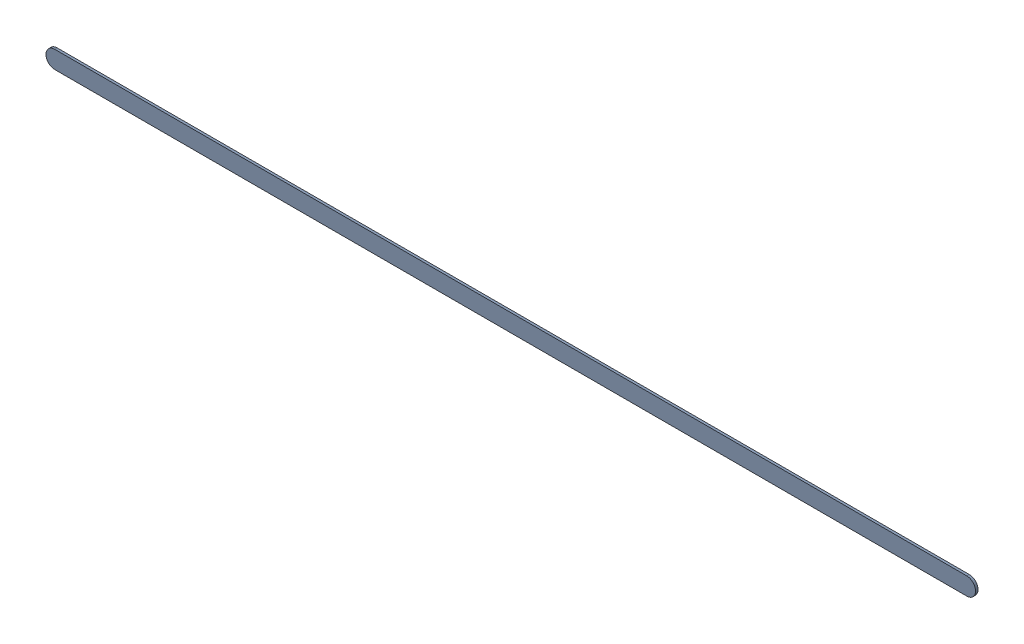
SolidWorks assembly Track (17.9mm,60.8mm)(31.1mm,60.8mm) on Top Layer, configuration Predeterminado. Lengths in mm.
Overall size (13.45 0.25 0.04).
2 component instances, 1 part files, 0 mates.
Components (placement in the parent):
- Track (17.9mm,60.8mm)(31.1mm,60.8mm) on Top Layer-1-1: Track (17.9mm,60.8mm)(31.1mm,60.8mm) on Top Layer-1 [Predeterminado] at (-68.317 -44.187 -0.0457) size (13.45 0.25 0.04)
  - Track (17.9mm,60.8mm)(31.1mm,60.8mm) on Top Layer-Part-1-1: Track (17.9mm,60.8mm)(31.1mm,60.8mm) on Top Layer-Part-1 [Predeterminado] at origin size (13.45 0.25 0.04)
